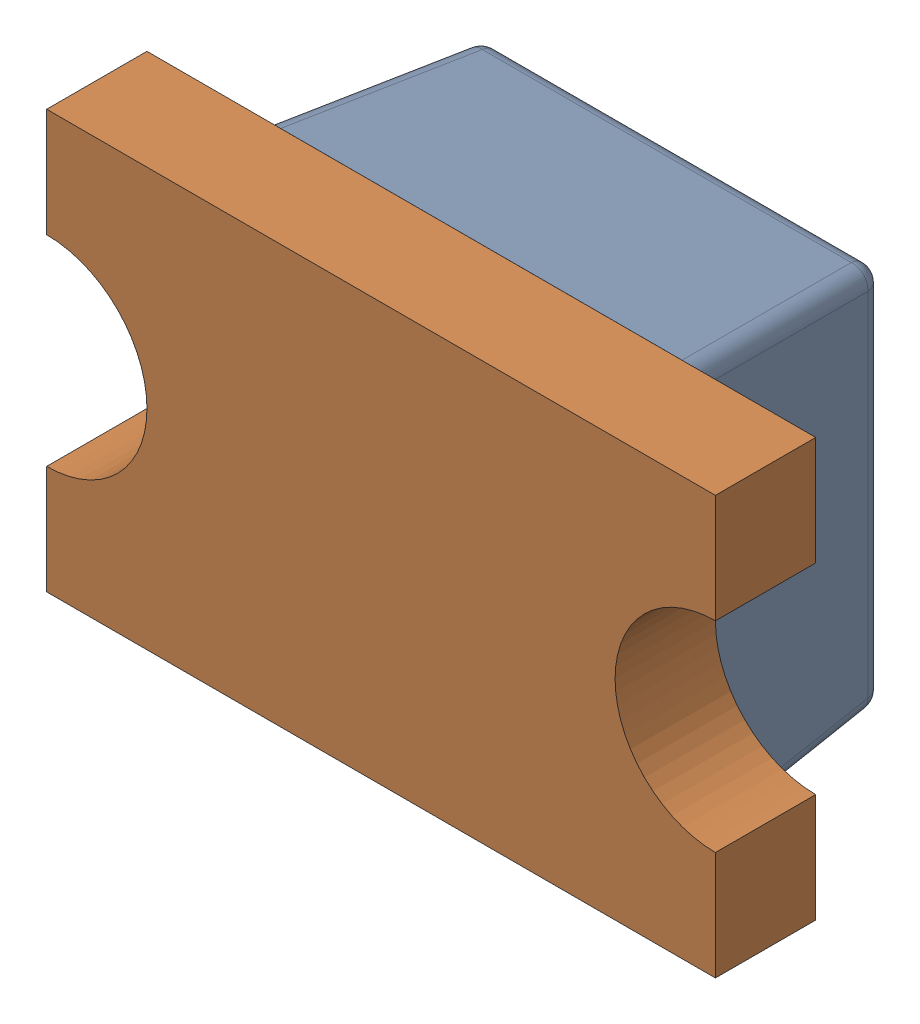
SolidWorks assembly D9_3, configuration Default. Lengths in mm.
Overall size (2 1.25 0.9).
2 component instances, 2 part files, 0 mates.
Components (placement in the parent):
- LED 0805 Lens RED-1: LED 0805 Lens RED [Default] at (145.9109 95.631 -1.2114) x (-1 0 0) z (0 -1 0) size (1.3 0.6 1.25)
- LED 0805 Base RED-1: LED 0805 Base RED [Default] at (145.9109 95.631 -1.2114) x (-1 0 0) z (0 -1 0) size (2 0.4 1.25)
